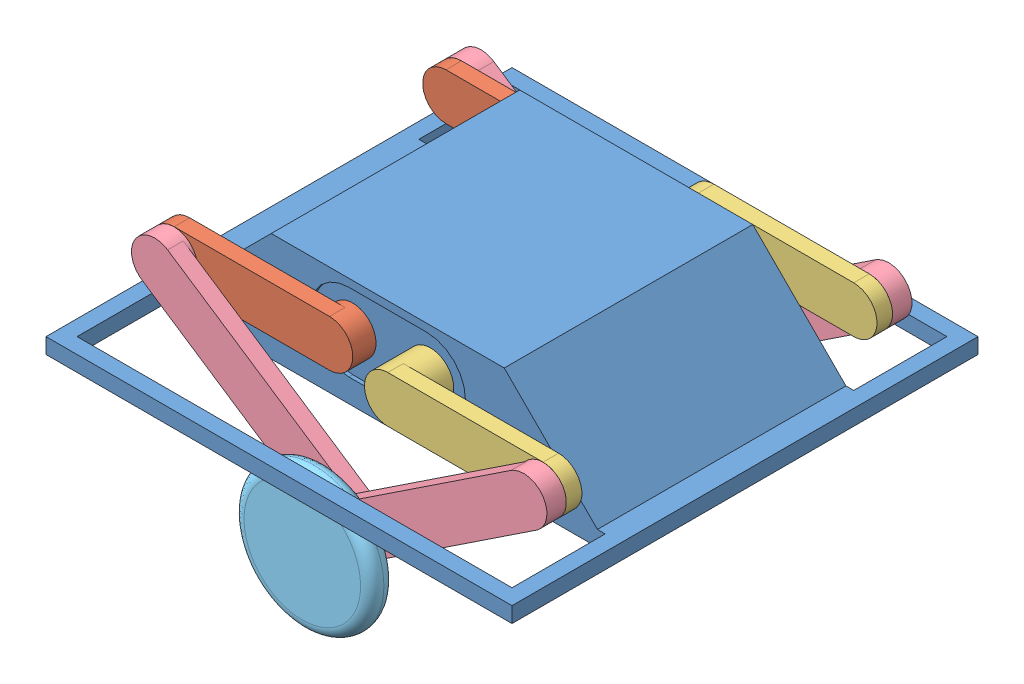
SolidWorks assembly Robot, configuration 默认. Lengths in mm.
Overall size (600 351.08 600).
11 component instances, 5 part files, 25 mates.
Components (placement in the parent):
- body-1: body [默认] at (-5.8221 11.1215 600) size (600 140 600)
- leg_1-1: leg_1 [默认] at (-55.8221 91.1215 765) x (0 0 1) z (-1 0 0) size (30 60 260)
- leg_1-2: leg_1 [默认] at (-55.8221 91.1215 435) x (0 0 -1) z (-1 0 0) size (30 60 260)
- leg_2-1: leg_2 [默认] at (44.1779 91.1215 790) x (0 0 1) z (1 0 0) size (55 60 260)
- leg_2-2: leg_2 [默认] at (44.1779 91.1215 410) x (0 0 -1) z (1 0 0) size (55 60 260)
- leg_3-1: leg_3 [默认] at (-5.8221 -74.7097 810) x (0 0 -1) z (0.833333 -0.552771 0) size (30 60 360)
- leg_3-2: leg_3 [默认] at (-5.8221 -74.7097 835) x (0 0 -1) z (-0.833333 -0.552771 0) size (30 60 360)
- leg_3-3: leg_3 [默认] at (-255.8221 91.1215 410) x (0 0 -1) z (-0.833333 0.552771 0) size (30 60 360)
- leg_3-4: leg_3 [默认] at (244.1779 91.1215 385) x (0 0 -1) z (0.833333 0.552771 0) size (30 60 360)
- wheel-1: wheel [默认] at (-5.8221 -74.7097 330) x (0 0 1) z (0.090312 0.995914 0) size (30 180 180)
- wheel-2: wheel [默认] at (-5.8221 -74.7097 840) x (0 0 1) z (-0.821699 0.569922 0) size (30 180 180)
Mates (geometry in assembly coordinates):
- 重合1: coincident anti-aligned: plane of body-1 through (44.1779 91.1215 755) normal (0 0 1); plane of leg_1-1 through (-55.8221 91.1215 755) normal (0 0 -1)
- 同心1: concentric anti-aligned: circle of body-1; circle of leg_1-1
- 重合2: coincident anti-aligned: plane of body-1 through (-55.8221 91.1215 445) normal (0 0 -1); plane of leg_1-2 through (-55.8221 91.1215 445) normal (0 0 1)
- 同心2: concentric anti-aligned: circle of body-1; circle of leg_1-2
- 重合3: coincident anti-aligned: plane of body-1 through (44.1779 91.1215 755) normal (0 0 1); plane of leg_2-1 through (44.1779 91.1215 755) normal (0 0 -1)
- 同心3: concentric anti-aligned: circle of body-1; circle of leg_2-1
- 重合4: coincident anti-aligned: plane of body-1 through (-55.8221 91.1215 445) normal (0 0 -1); plane of leg_2-2 through (44.1779 91.1215 445) normal (0 0 1)
- 同心4: concentric anti-aligned: circle of body-1; circle of leg_2-2
- 重合5: coincident anti-aligned: plane of leg_1-1 through (-55.8221 91.1215 785) normal (0 0 1); plane of leg_3-1 through (-255.8221 91.1215 785) normal (0 0 -1)
- 重合6: coincident anti-aligned: circle of leg_1-1; circle of leg_3-1
- 重合7: coincident anti-aligned: circle of leg_2-1; circle of leg_3-2
- 同心5: concentric anti-aligned: circle of leg_3-1; circle of leg_3-2
- 同心6: concentric anti-aligned: circle of leg_1-2; circle of leg_3-3
- 重合8: coincident anti-aligned: plane of leg_1-2 through (-55.8221 91.1215 415) normal (0 0 -1); plane of leg_3-3 through (-255.8221 91.1215 415) normal (0 0 1)
- 重合9: coincident anti-aligned: plane of leg_2-2 through (44.1779 91.1215 390) normal (0 0 -1); plane of leg_3-4 through (244.1779 91.1215 390) normal (0 0 1)
- 同心9: concentric anti-aligned: circle of leg_2-2; circle of leg_3-4
- 重合11: coincident aligned: circle of leg_3-3; circle of leg_3-4
- 同心10: concentric aligned: circle of leg_3-4; circle of wheel-1
- 重合12: coincident anti-aligned: plane of leg_3-4 through (-5.8221 -74.7097 360) normal (0 0 -1); plane of wheel-1 through (-5.8221 -74.7097 360) normal (0 0 1)
- 同心11: concentric anti-aligned: circle of leg_3-2; circle of wheel-2
- 重合13: coincident anti-aligned: plane of leg_3-2 through (-5.8221 -74.7097 840) normal (0 0 1); plane of wheel-2 through (-5.8221 -74.7097 840) normal (0 0 -1)
- 平行1: parallel aligned: line of body-1 through (144.1779 151.1215 760) axis (-1 0 0); line of leg_1-1 through (-55.8221 121.1215 785) axis (-1 0 0)
- 平行2: parallel aligned: line of body-1 through (144.1779 151.1215 760) axis (-1 0 0); line of leg_2-1 through (244.1779 121.1215 810) axis (-1 0 0)
- 平行3: parallel anti-aligned: line of body-1 through (144.1779 151.1215 440) axis (-1 0 0); line of leg_2-2 through (44.1779 121.1215 390) axis (1 0 0)
- 平行4: parallel anti-aligned: line of body-1 through (144.1779 151.1215 440) axis (-1 0 0); line of leg_1-2 through (-255.8221 121.1215 415) axis (1 0 0)
